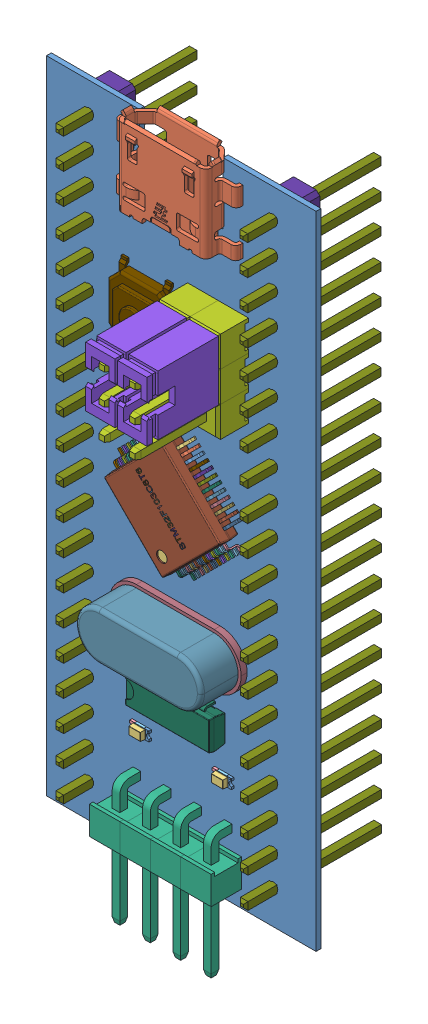
SolidWorks assembly User Library-BluePill, configuration Default. Lengths in mm.
Overall size (22.5 58.64 17.43).
114 component instances, 80 part files, 0 mates.
Components (placement in the parent):
- User Library-BluePill_Board-1: User Library-BluePill_Board [Default] at (0 0 -0.4115) size (22.5 53.5 0.41)
- User Library-BluePill_Free-Models-1: User Library-BluePill_Free-Models [Default] at origin size (17.88 58.64 17.43)
  - User Library-BluePill_2040343-2-1: User Library-BluePill_2040343-2 [Default] at (0.0632 26.558 0.508) x (-1 0 0) z (0 1 0) size (10.2 2.83 7.23)
  - User Library-BluePill_STM32F103C8T6-1: User Library-BluePill_STM32F103C8T6 [Default] x (-0.707107 0.707107 0) z (0 0 1) size (9 9 1.61)
    - User Library-BluePill_User_Library-LQFP50P900X900X160_Designator1_103#741422048_1#Open__CASCADE_STEP_translator_6.8_1.1;Open_CASCADE_STEP_translator_6.8_1.1-1: User Library-BluePill_User_Library-LQFP50P900X900X160_Designator1_103#741422048_1#Open__CASCADE_STEP_translator_6.8_1.1;Open_CASCADE_STEP_translator_6.8_1.1 [Default] at origin size (0.87 0.88 0)
    - User Library-BluePill_User_Library-LQFP50P900X900X160_Designator1_103#741422048__4#Leader;Leader-1: User Library-BluePill_User_Library-LQFP50P900X900X160_Designator1_103#741422048__4#Leader;Leader [Default] at origin size (1 0.22 0.88)
    - User Library-BluePill_User_Library-LQFP50P900X900X160_Designator1_103#741422048__5#Leader;Leader-1: User Library-BluePill_User_Library-LQFP50P900X900X160_Designator1_103#741422048__5#Leader;Leader [Default] at origin size (1 0.22 0.88)
    - User Library-BluePill_User_Library-LQFP50P900X900X160_Designator1_103#741422048__6#Leader;Leader-1: User Library-BluePill_User_Library-LQFP50P900X900X160_Designator1_103#741422048__6#Leader;Leader [Default] at origin size (1 0.22 0.88)
    - User Library-BluePill_User_Library-LQFP50P900X900X160_Designator1_103#741422048__7#Leader;Leader-1: User Library-BluePill_User_Library-LQFP50P900X900X160_Designator1_103#741422048__7#Leader;Leader [Default] at origin size (1 0.22 0.88)
    - User Library-BluePill_User_Library-LQFP50P900X900X160_Designator1_103#741422048__8#Leader;Leader-1: User Library-BluePill_User_Library-LQFP50P900X900X160_Designator1_103#741422048__8#Leader;Leader [Default] at origin size (1 0.22 0.88)
    - User Library-BluePill_User_Library-LQFP50P900X900X160_Designator1_103#741422048__9#Leader;Leader-1: User Library-BluePill_User_Library-LQFP50P900X900X160_Designator1_103#741422048__9#Leader;Leader [Default] at origin size (1 0.22 0.88)
    - User Library-BluePill_User_Library-LQFP50P900X900X160_Designator1_103#741422048__10#Leader;Leader-1: User Library-BluePill_User_Library-LQFP50P900X900X160_Designator1_103#741422048__10#Leader;Leader [Default] at origin size (1 0.22 0.88)
    - User Library-BluePill_User_Library-LQFP50P900X900X160_Designator1_103#741422048__11#Leader;Leader-1: User Library-BluePill_User_Library-LQFP50P900X900X160_Designator1_103#741422048__11#Leader;Leader [Default] at origin size (1 0.22 0.88)
    - User Library-BluePill_User_Library-LQFP50P900X900X160_Designator1_103#741422048__12#Leader;Leader-1: User Library-BluePill_User_Library-LQFP50P900X900X160_Designator1_103#741422048__12#Leader;Leader [Default] at origin size (1 0.22 0.88)
    - User Library-BluePill_User_Library-LQFP50P900X900X160_Designator1_103#741422048__13#Leader;Leader-1: User Library-BluePill_User_Library-LQFP50P900X900X160_Designator1_103#741422048__13#Leader;Leader [Default] at origin size (1 0.22 0.88)
    - User Library-BluePill_User_Library-LQFP50P900X900X160_Designator1_103#741422048__14#Leader;Leader-1: User Library-BluePill_User_Library-LQFP50P900X900X160_Designator1_103#741422048__14#Leader;Leader [Default] at origin size (1 0.22 0.88)
    - User Library-BluePill_User_Library-LQFP50P900X900X160_Designator1_103#741422048__15#Leader;Leader-1: User Library-BluePill_User_Library-LQFP50P900X900X160_Designator1_103#741422048__15#Leader;Leader [Default] at origin size (1 0.22 0.88)
    - User Library-BluePill_User_Library-LQFP50P900X900X160_Designator1_103#741422048__16#Leader;Leader-1: User Library-BluePill_User_Library-LQFP50P900X900X160_Designator1_103#741422048__16#Leader;Leader [Default] at origin size (1 0.22 0.88)
    - User Library-BluePill_User_Library-LQFP50P900X900X160_Designator1_103#741422048__17#Leader;Leader-1: User Library-BluePill_User_Library-LQFP50P900X900X160_Designator1_103#741422048__17#Leader;Leader [Default] at origin size (1 0.22 0.88)
    - User Library-BluePill_User_Library-LQFP50P900X900X160_Designator1_103#741422048__18#Leader;Leader-1: User Library-BluePill_User_Library-LQFP50P900X900X160_Designator1_103#741422048__18#Leader;Leader [Default] at origin size (1 0.22 0.88)
    - User Library-BluePill_User_Library-LQFP50P900X900X160_Designator1_103#741422048__19#Leader;Leader-1: User Library-BluePill_User_Library-LQFP50P900X900X160_Designator1_103#741422048__19#Leader;Leader [Default] at origin size (1 0.22 0.88)
    - User Library-BluePill_User_Library-LQFP50P900X900X160_Designator1_103#741422048__20#Leader;Leader-1: User Library-BluePill_User_Library-LQFP50P900X900X160_Designator1_103#741422048__20#Leader;Leader [Default] at origin size (1 0.22 0.88)
    - User Library-BluePill_User_Library-LQFP50P900X900X160_Designator1_103#741422048__21#Leader;Leader-1: User Library-BluePill_User_Library-LQFP50P900X900X160_Designator1_103#741422048__21#Leader;Leader [Default] at origin size (1 0.22 0.88)
    - User Library-BluePill_User_Library-LQFP50P900X900X160_Designator1_103#741422048__22#Leader;Leader-1: User Library-BluePill_User_Library-LQFP50P900X900X160_Designator1_103#741422048__22#Leader;Leader [Default] at origin size (1 0.22 0.88)
    - User Library-BluePill_User_Library-LQFP50P900X900X160_Designator1_103#741422048__23#Leader;Leader-1: User Library-BluePill_User_Library-LQFP50P900X900X160_Designator1_103#741422048__23#Leader;Leader [Default] at origin size (1 0.22 0.88)
    - User Library-BluePill_User_Library-LQFP50P900X900X160_Designator1_103#741422048__24#Leader;Leader-1: User Library-BluePill_User_Library-LQFP50P900X900X160_Designator1_103#741422048__24#Leader;Leader [Default] at origin size (1 0.22 0.88)
    - User Library-BluePill_User_Library-LQFP50P900X900X160_Designator1_103#741422048__25#Leader;Leader-1: User Library-BluePill_User_Library-LQFP50P900X900X160_Designator1_103#741422048__25#Leader;Leader [Default] at origin size (1 0.22 0.88)
    - User Library-BluePill_User_Library-LQFP50P900X900X160_Designator1_103#741422048__26#Leader;Leader-1: User Library-BluePill_User_Library-LQFP50P900X900X160_Designator1_103#741422048__26#Leader;Leader [Default] at origin size (1 0.22 0.88)
    - User Library-BluePill_User_Library-LQFP50P900X900X160_Designator1_103#741422048__27#Leader;Leader-1: User Library-BluePill_User_Library-LQFP50P900X900X160_Designator1_103#741422048__27#Leader;Leader [Default] at origin size (1 0.22 0.88)
    - User Library-BluePill_User_Library-LQFP50P900X900X160_Designator1_103#741422048__28#Leader;Leader-1: User Library-BluePill_User_Library-LQFP50P900X900X160_Designator1_103#741422048__28#Leader;Leader [Default] at origin size (0.22 1 0.88)
    - User Library-BluePill_User_Library-LQFP50P900X900X160_Designator1_103#741422048__29#Leader;Leader-1: User Library-BluePill_User_Library-LQFP50P900X900X160_Designator1_103#741422048__29#Leader;Leader [Default] at origin size (0.22 1 0.88)
    - User Library-BluePill_User_Library-LQFP50P900X900X160_Designator1_103#741422048__30#Leader;Leader-1: User Library-BluePill_User_Library-LQFP50P900X900X160_Designator1_103#741422048__30#Leader;Leader [Default] at origin size (0.22 1 0.88)
    - User Library-BluePill_User_Library-LQFP50P900X900X160_Designator1_103#741422048__31#Leader;Leader-1: User Library-BluePill_User_Library-LQFP50P900X900X160_Designator1_103#741422048__31#Leader;Leader [Default] at origin size (0.22 1 0.88)
    - User Library-BluePill_User_Library-LQFP50P900X900X160_Designator1_103#741422048__32#Leader;Leader-1: User Library-BluePill_User_Library-LQFP50P900X900X160_Designator1_103#741422048__32#Leader;Leader [Default] at origin size (0.22 1 0.88)
    - User Library-BluePill_User_Library-LQFP50P900X900X160_Designator1_103#741422048__33#Leader;Leader-1: User Library-BluePill_User_Library-LQFP50P900X900X160_Designator1_103#741422048__33#Leader;Leader [Default] at origin size (0.22 1 0.88)
    - User Library-BluePill_User_Library-LQFP50P900X900X160_Designator1_103#741422048__34#Leader;Leader-1: User Library-BluePill_User_Library-LQFP50P900X900X160_Designator1_103#741422048__34#Leader;Leader [Default] at origin size (0.22 1 0.88)
    - User Library-BluePill_User_Library-LQFP50P900X900X160_Designator1_103#741422048__35#Leader;Leader-1: User Library-BluePill_User_Library-LQFP50P900X900X160_Designator1_103#741422048__35#Leader;Leader [Default] at origin size (0.22 1 0.88)
    - User Library-BluePill_User_Library-LQFP50P900X900X160_Designator1_103#741422048__36#Leader;Leader-1: User Library-BluePill_User_Library-LQFP50P900X900X160_Designator1_103#741422048__36#Leader;Leader [Default] at origin size (0.22 1 0.88)
    - User Library-BluePill_User_Library-LQFP50P900X900X160_Designator1_103#741422048__37#Leader;Leader-1: User Library-BluePill_User_Library-LQFP50P900X900X160_Designator1_103#741422048__37#Leader;Leader [Default] at origin size (0.22 1 0.88)
    - User Library-BluePill_User_Library-LQFP50P900X900X160_Designator1_103#741422048__38#Leader;Leader-1: User Library-BluePill_User_Library-LQFP50P900X900X160_Designator1_103#741422048__38#Leader;Leader [Default] at origin size (0.22 1 0.88)
    - User Library-BluePill_User_Library-LQFP50P900X900X160_Designator1_103#741422048__39#Leader;Leader-1: User Library-BluePill_User_Library-LQFP50P900X900X160_Designator1_103#741422048__39#Leader;Leader [Default] at origin size (0.22 1 0.88)
    - User Library-BluePill_User_Library-LQFP50P900X900X160_Designator1_103#741422048__40#Leader;Leader-1: User Library-BluePill_User_Library-LQFP50P900X900X160_Designator1_103#741422048__40#Leader;Leader [Default] at origin size (0.22 1 0.88)
    - User Library-BluePill_User_Library-LQFP50P900X900X160_Designator1_103#741422048__41#Leader;Leader-1: User Library-BluePill_User_Library-LQFP50P900X900X160_Designator1_103#741422048__41#Leader;Leader [Default] at origin size (0.22 1 0.88)
    - User Library-BluePill_User_Library-LQFP50P900X900X160_Designator1_103#741422048__42#Leader;Leader-1: User Library-BluePill_User_Library-LQFP50P900X900X160_Designator1_103#741422048__42#Leader;Leader [Default] at origin size (0.22 1 0.88)
    - User Library-BluePill_User_Library-LQFP50P900X900X160_Designator1_103#741422048__43#Leader;Leader-1: User Library-BluePill_User_Library-LQFP50P900X900X160_Designator1_103#741422048__43#Leader;Leader [Default] at origin size (0.22 1 0.88)
    - User Library-BluePill_User_Library-LQFP50P900X900X160_Designator1_103#741422048__44#Leader;Leader-1: User Library-BluePill_User_Library-LQFP50P900X900X160_Designator1_103#741422048__44#Leader;Leader [Default] at origin size (0.22 1 0.88)
    - User Library-BluePill_User_Library-LQFP50P900X900X160_Designator1_103#741422048__45#Leader;Leader-1: User Library-BluePill_User_Library-LQFP50P900X900X160_Designator1_103#741422048__45#Leader;Leader [Default] at origin size (0.22 1 0.88)
    - User Library-BluePill_User_Library-LQFP50P900X900X160_Designator1_103#741422048__46#Leader;Leader-1: User Library-BluePill_User_Library-LQFP50P900X900X160_Designator1_103#741422048__46#Leader;Leader [Default] at origin size (0.22 1 0.88)
    - User Library-BluePill_User_Library-LQFP50P900X900X160_Designator1_103#741422048__47#Leader;Leader-1: User Library-BluePill_User_Library-LQFP50P900X900X160_Designator1_103#741422048__47#Leader;Leader [Default] at origin size (0.22 1 0.88)
    - User Library-BluePill_User_Library-LQFP50P900X900X160_Designator1_103#741422048__48#Leader;Leader-1: User Library-BluePill_User_Library-LQFP50P900X900X160_Designator1_103#741422048__48#Leader;Leader [Default] at origin size (0.22 1 0.88)
    - User Library-BluePill_User_Library-LQFP50P900X900X160_Designator1_103#741422048__49#Leader;Leader-1: User Library-BluePill_User_Library-LQFP50P900X900X160_Designator1_103#741422048__49#Leader;Leader [Default] at origin size (0.22 1 0.88)
    - User Library-BluePill_User_Library-LQFP50P900X900X160_Designator1_103#741422048__50#Leader;Leader-1: User Library-BluePill_User_Library-LQFP50P900X900X160_Designator1_103#741422048__50#Leader;Leader [Default] at origin size (0.22 1 0.88)
    - User Library-BluePill_User_Library-LQFP50P900X900X160_Designator1_103#741422048__51#Leader;Leader-1: User Library-BluePill_User_Library-LQFP50P900X900X160_Designator1_103#741422048__51#Leader;Leader [Default] at origin size (0.22 1 0.88)
    - User Library-BluePill_User_Library-LQFP50P900X900X160_1-1: User Library-BluePill_User_Library-LQFP50P900X900X160_1 [Default] at origin size (0.35 0.53 0.02)
    - User Library-BluePill_User_Library-LQFP50P900X900X160_2-1: User Library-BluePill_User_Library-LQFP50P900X900X160_2 [Default] at origin size (0.4 0.5 0.02)
    - User Library-BluePill_User_Library-LQFP50P900X900X160_3-1: User Library-BluePill_User_Library-LQFP50P900X900X160_3 [Default] at origin size (0.34 0.53 0.02)
    - User Library-BluePill_User_Library-LQFP50P900X900X160_4-1: User Library-BluePill_User_Library-LQFP50P900X900X160_4 [Default] at origin size (0.45 0.54 0.02)
    - User Library-BluePill_User_Library-LQFP50P900X900X160_5-1: User Library-BluePill_User_Library-LQFP50P900X900X160_5 [Default] at origin size (0.34 0.53 0.02)
    - User Library-BluePill_User_Library-LQFP50P900X900X160_6-1: User Library-BluePill_User_Library-LQFP50P900X900X160_6 [Default] at origin size (0.35 0.53 0.02)
    - User Library-BluePill_User_Library-LQFP50P900X900X160_7-1: User Library-BluePill_User_Library-LQFP50P900X900X160_7 [Default] at origin size (0.18 0.5 0.02)
    - User Library-BluePill_User_Library-LQFP50P900X900X160_8-1: User Library-BluePill_User_Library-LQFP50P900X900X160_8 [Default] at origin size (0.34 0.5 0.02)
    - User Library-BluePill_User_Library-LQFP50P900X900X160_9-1: User Library-BluePill_User_Library-LQFP50P900X900X160_9 [Default] at origin size (0.34 0.51 0.02)
    - User Library-BluePill_User_Library-LQFP50P900X900X160_10-1: User Library-BluePill_User_Library-LQFP50P900X900X160_10 [Default] at origin size (0.34 0.53 0.02)
    - User Library-BluePill_User_Library-LQFP50P900X900X160_11-1: User Library-BluePill_User_Library-LQFP50P900X900X160_11 [Default] at origin size (0.48 0.5 0.02)
    - User Library-BluePill_User_Library-LQFP50P900X900X160_12-1: User Library-BluePill_User_Library-LQFP50P900X900X160_12 [Default] at origin size (0.4 0.5 0.02)
    - User Library-BluePill_User_Library-LQFP50P900X900X160_13-1: User Library-BluePill_User_Library-LQFP50P900X900X160_13 [Default] at origin size (0.41 0.52 0.02)
    - User Library-BluePill_User_Library-LQFP50P900X900X160_Designator1_103#741422048_3#Body__2#Open_CASCADE_STEP_translator_6.8_1.2.1;Open_CASCADE_STEP_translator__6.8_1.2.1-1: User Library-BluePill_User_Library-LQFP50P900X900X160_Designator1_103#741422048_3#Body__2#Open_CASCADE_STEP_translator_6.8_1.2.1;Open_CASCADE_STEP_translator__6.8_1.2.1 [Default] at origin size (7.01 7.01 1.56)
  - User Library-BluePill_User_Library-HC49S-1-1: User Library-BluePill_User_Library-HC49S-1 [Default] at (-2.4146 -9.7127 0) size (10.98 4.49 6.6)
    - User Library-BluePill_User_Library-HC49S-1_Fusion-1: User Library-BluePill_User_Library-HC49S-1_Fusion [Default] at origin size (5.32 0.44 3)
    - User Library-BluePill_User_Library-HC49S-1_Fillet-1: User Library-BluePill_User_Library-HC49S-1_Fillet [Default] at origin size (10.98 4.49 0.5)
    - User Library-BluePill_User_Library-HC49S-1_Fillet002-1: User Library-BluePill_User_Library-HC49S-1_Fillet002 [Default] at origin size (10.48 3.99 3.5)
  - User Library-BluePill_SW3dPS-EA96-1: User Library-BluePill_SW3dPS-EA96 [Default] at (0.1524 -14.6506 0) size (7.1 3.1 1.5)
  - User Library-BluePill_User_Library-Header_Male_10Pin-1: User Library-BluePill_User_Library-Header_Male_10Pin [Default] at (7.6712 24.13 -0.381) x (0 -1 0) z (0 0 -1) size (25.4 2.49 11.54)
    - User Library-BluePill_User_Library-Header_Male_10Pin_PinArray-1: User Library-BluePill_User_Library-Header_Male_10Pin_PinArray [Default] at origin size (23.5 0.64 11.54)
    - User Library-BluePill_User_Library-Header_Male_10Pin_BodyArray-1: User Library-BluePill_User_Library-Header_Male_10Pin_BodyArray [Default] at origin size (25.4 2.49 2.29)
  - User Library-BluePill_User_Library-Header_Male_10Pin-2: User Library-BluePill_User_Library-Header_Male_10Pin [Default] at (7.6962 -1.27 -0.381) x (0 -1 0) z (0 0 -1) size (25.4 2.49 11.54)
    - User Library-BluePill_User_Library-Header_Male_10Pin_PinArray-1: User Library-BluePill_User_Library-Header_Male_10Pin_PinArray [Default] at origin size (23.5 0.64 11.54)
    - User Library-BluePill_User_Library-Header_Male_10Pin_BodyArray-1: User Library-BluePill_User_Library-Header_Male_10Pin_BodyArray [Default] at origin size (25.4 2.49 2.29)
  - User Library-BluePill_User_Library-Header_Male_10Pin-3: User Library-BluePill_User_Library-Header_Male_10Pin [Default] at (-7.6958 -1.27 -0.381) x (0 -1 0) z (0 0 -1) size (25.4 2.49 11.54)
    - User Library-BluePill_User_Library-Header_Male_10Pin_PinArray-1: User Library-BluePill_User_Library-Header_Male_10Pin_PinArray [Default] at origin size (23.5 0.64 11.54)
    - User Library-BluePill_User_Library-Header_Male_10Pin_BodyArray-1: User Library-BluePill_User_Library-Header_Male_10Pin_BodyArray [Default] at origin size (25.4 2.49 2.29)
  - User Library-BluePill_User_Library-Header_Male_10Pin-4: User Library-BluePill_User_Library-Header_Male_10Pin [Default] at (-7.6958 24.13 -0.381) x (0 -1 0) z (0 0 -1) size (25.4 2.49 11.54)
    - User Library-BluePill_User_Library-Header_Male_10Pin_PinArray-1: User Library-BluePill_User_Library-Header_Male_10Pin_PinArray [Default] at origin size (23.5 0.64 11.54)
    - User Library-BluePill_User_Library-Header_Male_10Pin_BodyArray-1: User Library-BluePill_User_Library-Header_Male_10Pin_BodyArray [Default] at origin size (25.4 2.49 2.29)
  - User Library-BluePill_User_Library-4x4_SMD_Switch-1: User Library-BluePill_User_Library-4x4_SMD_Switch [Default] at (-2.7432 12.1666 0) x (0 1 0) z (1 0 0) size (6.4 1.5 5.2)
  - User Library-BluePill_User_Library-LED_0603_WS-1: User Library-BluePill_User_Library-LED_0603_WS [Default] at (-3.2766 -18.2372 0) x (-1 0 0) z (0 0 1) size (1.6 0.8 0.6)
    - User Library-BluePill_User_Library-LED_0603_WS_Pocket002-1: User Library-BluePill_User_Library-LED_0603_WS_Pocket002 [Default] at origin size (0.4 0.8 0.2)
    - User Library-BluePill_User_Library-LED_0603_WS_Pad004-1: User Library-BluePill_User_Library-LED_0603_WS_Pad004 [Default] x (1 0 0) z (0 0 -1) size (0.4 0.8 0)
    - User Library-BluePill_User_Library-LED_0603_WS_Fillet-1: User Library-BluePill_User_Library-LED_0603_WS_Fillet [Default] at origin size (1 0.7 0.4)
    - User Library-BluePill_User_Library-LED_0603_WS_Pocket001-1: User Library-BluePill_User_Library-LED_0603_WS_Pocket001 [Default] at origin size (0.4 0.8 0.2)
    - User Library-BluePill_User_Library-LED_0603_WS_Pad-1: User Library-BluePill_User_Library-LED_0603_WS_Pad [Default] at origin size (0.8 0.8 0.2)
  - User Library-BluePill_User_Library-LED_0603_WS-2: User Library-BluePill_User_Library-LED_0603_WS [Default] at (3.6068 -18.2372 0) x (-1 0 0) z (0 0 1) size (1.6 0.8 0.6)
    - User Library-BluePill_User_Library-LED_0603_WS_Pocket002-1: User Library-BluePill_User_Library-LED_0603_WS_Pocket002 [Default] at origin size (0.4 0.8 0.2)
    - User Library-BluePill_User_Library-LED_0603_WS_Pad004-1: User Library-BluePill_User_Library-LED_0603_WS_Pad004 [Default] x (1 0 0) z (0 0 -1) size (0.4 0.8 0)
    - User Library-BluePill_User_Library-LED_0603_WS_Fillet-1: User Library-BluePill_User_Library-LED_0603_WS_Fillet [Default] at origin size (1 0.7 0.4)
    - User Library-BluePill_User_Library-LED_0603_WS_Pocket001-1: User Library-BluePill_User_Library-LED_0603_WS_Pocket001 [Default] at origin size (0.4 0.8 0.2)
    - User Library-BluePill_User_Library-LED_0603_WS_Pad-1: User Library-BluePill_User_Library-LED_0603_WS_Pad [Default] at origin size (0.8 0.8 0.2)
  - User Library-BluePill_User_Library-header90-4-1: User Library-BluePill_User_Library-header90-4 [Default] at (6.4464 -32.8991 9.652) x (1 0 0) z (0 0 -1) size (10.16 10.41 5.54)
    - User Library-BluePill_User_Library-header90-4_Header90-1-1: User Library-BluePill_User_Library-header90-4_Header90-1 [Default] at (-10.1293 -8.5207 8.231) size (2.54 10.41 5.54)
    - User Library-BluePill_User_Library-header90-4_Header90-1-2: User Library-BluePill_User_Library-header90-4_Header90-1 [Default] at (-7.5893 -8.5207 8.231) size (2.54 10.41 5.54)
    - User Library-BluePill_User_Library-header90-4_Header90-1-3: User Library-BluePill_User_Library-header90-4_Header90-1 [Default] at (-5.0493 -8.5207 8.231) size (2.54 10.41 5.54)
    - User Library-BluePill_User_Library-header90-4_Header90-1-4: User Library-BluePill_User_Library-header90-4_Header90-1 [Default] at (-2.5093 -8.5207 8.231) size (2.54 10.41 5.54)
  - User Library-BluePill_User_Library-Header3x2_100_TH-1: User Library-BluePill_User_Library-Header3x2_100_TH [Default] at (3.0988 12.1666 0) x (1 0 0) z (0 -1 0) size (5.08 10.98 7.62)
    - User Library-BluePill_User_Library-Header3x2_100_TH_User_Library-Header1x2-1: User Library-BluePill_User_Library-Header3x2_100_TH_User_Library-Header1x2 [Default] at (-5.6755 -6.84 9.2218) size (5.08 10.98 2.54)
      - User Library-BluePill_User_Library-Header3x2_100_TH_User_Library-Header1x2_Header1_1-1: User Library-BluePill_User_Library-Header3x2_100_TH_User_Library-Header1x2_Header1_1 [Default] at (4.4052 8.1155 -11.7669) size (2.54 10.98 2.54)
      - User Library-BluePill_User_Library-Header3x2_100_TH_User_Library-Header1x2_Header1_1-2: User Library-BluePill_User_Library-Header3x2_100_TH_User_Library-Header1x2_Header1_1 [Default] at (6.9452 8.1155 -11.7669) size (2.54 10.98 2.54)
    - User Library-BluePill_User_Library-Header3x2_100_TH_User_Library-Header1x2-2: User Library-BluePill_User_Library-Header3x2_100_TH_User_Library-Header1x2 [Default] at (-5.6755 -6.84 11.7618) size (5.08 10.98 2.54)
      - User Library-BluePill_User_Library-Header3x2_100_TH_User_Library-Header1x2_Header1_1-1: User Library-BluePill_User_Library-Header3x2_100_TH_User_Library-Header1x2_Header1_1 [Default] at (4.4052 8.1155 -11.7669) size (2.54 10.98 2.54)
      - User Library-BluePill_User_Library-Header3x2_100_TH_User_Library-Header1x2_Header1_1-2: User Library-BluePill_User_Library-Header3x2_100_TH_User_Library-Header1x2_Header1_1 [Default] at (6.9452 8.1155 -11.7669) size (2.54 10.98 2.54)
    - User Library-BluePill_User_Library-Header3x2_100_TH_User_Library-Header1x2-3: User Library-BluePill_User_Library-Header3x2_100_TH_User_Library-Header1x2 [Default] at (-5.6755 -6.84 14.3018) size (5.08 10.98 2.54)
      - User Library-BluePill_User_Library-Header3x2_100_TH_User_Library-Header1x2_Header1_1-1: User Library-BluePill_User_Library-Header3x2_100_TH_User_Library-Header1x2_Header1_1 [Default] at (4.4052 8.1155 -11.7669) size (2.54 10.98 2.54)
      - User Library-BluePill_User_Library-Header3x2_100_TH_User_Library-Header1x2_Header1_1-2: User Library-BluePill_User_Library-Header3x2_100_TH_User_Library-Header1x2_Header1_1 [Default] at (6.9452 8.1155 -11.7669) size (2.54 10.98 2.54)
  - User Library-BluePill_jumper_akspt_g-grey-1: User Library-BluePill_jumper_akspt_g-grey [Default] at (4.445 13.462 2.54) x (0 1 0) z (1 0 0) size (4.98 5.97 2.44)
  - User Library-BluePill_jumper_akspt_g-grey-2: User Library-BluePill_jumper_akspt_g-grey [Default] at (1.778 13.462 2.54) x (0 1 0) z (1 0 0) size (4.98 5.97 2.44)
